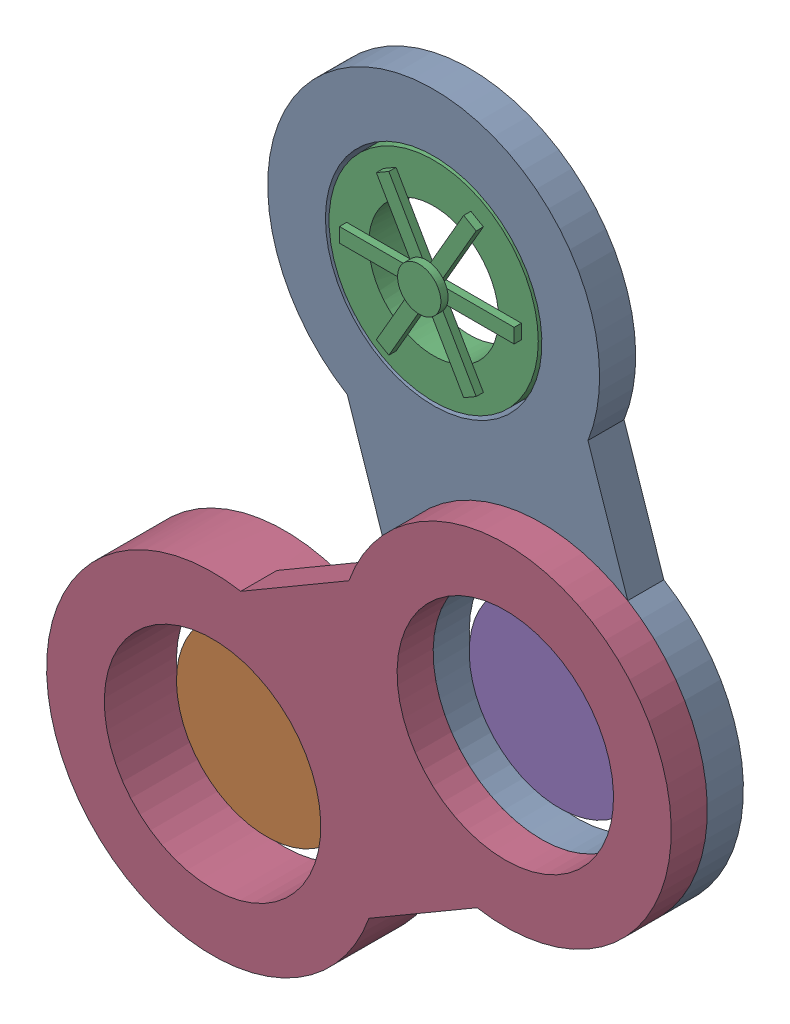
SolidWorks assembly Assem1, configuration Default. Lengths in mm.
Overall size (1035.02 1288.67 105.77).
5 component instances, 4 part files, 8 mates.
Components (placement in the parent):
- Part1-1: Part1 [Default] at (-1.3029 951.3423 695.602) x (-0.317638 0.948212 0) z (0 0 1) size (930 460 50)
- Part3-1: Part3 [Default] at (-327.6341 477.0669 695.602) x (0.923728 0.383049 0) z (0 0 -1) size (250 250 25)
- Part2-1: Part2 [Default] at (-71.1832 1159.949 695.602) size (290 290 75.77)
- Part4-1: Part4 [Default] at (-111.8146 603.249 745.602) x (0.863278 0.504729 0) z (0 0 1) size (930 460 100)
- Part3-2: Part3 [Default] at (78.1066 714.2893 695.602) x (0.923728 0.383049 0) z (0 0 -1) size (250 250 25)
Mates (geometry in assembly coordinates):
- Coincident1: coincident aligned: circle of Part1-1; cylinder of Part4-1 through (78.1066 714.2893 720.602) axis (0 0 1) radius 150
- Coincident2: coincident anti-aligned: plane of Part1-1 through (-1.3029 951.3423 720.602) normal (0 0 1); plane of Part4-1 through (-111.8146 603.249 720.602) normal (0 0 -1)
- Concentric1: concentric aligned: cylinder of Part1-1 through (-71.1832 1159.949 670.602) axis (0 0 1) radius 150; cylinder of Part2-1 through (-71.1832 1159.949 670.602) axis (0 0 1) radius 145
- Coincident3: coincident aligned: plane of Part1-1 through (-1.3029 951.3423 670.602) normal (0 0 -1); plane of Part2-1 through (-71.1832 1159.949 670.602) normal (0 0 -1)
- Concentric2: concentric aligned: cylinder of Part3-1 through (-327.6341 477.0669 670.602) axis (0 0 1) radius 100; cylinder of Part4-1 through (-327.6341 477.0669 720.602) axis (0 0 1) radius 150
- Coincident6: coincident aligned: plane of Part3-1 through (-327.6341 477.0669 670.602) normal (0 0 -1); plane of Part4-1 through (-111.8146 603.249 670.602) normal (0 0 -1)
- Concentric3: concentric aligned: cylinder of Part1-1 through (78.1066 714.2893 670.602) axis (0 0 1) radius 150; cylinder of Part3-2 through (78.1066 714.2893 670.602) axis (0 0 1) radius 100
- Coincident7: coincident aligned: plane of Part1-1 through (-1.3029 951.3423 670.602) normal (0 0 -1); plane of Part3-2 through (78.1066 714.2893 670.602) normal (0 0 -1)
